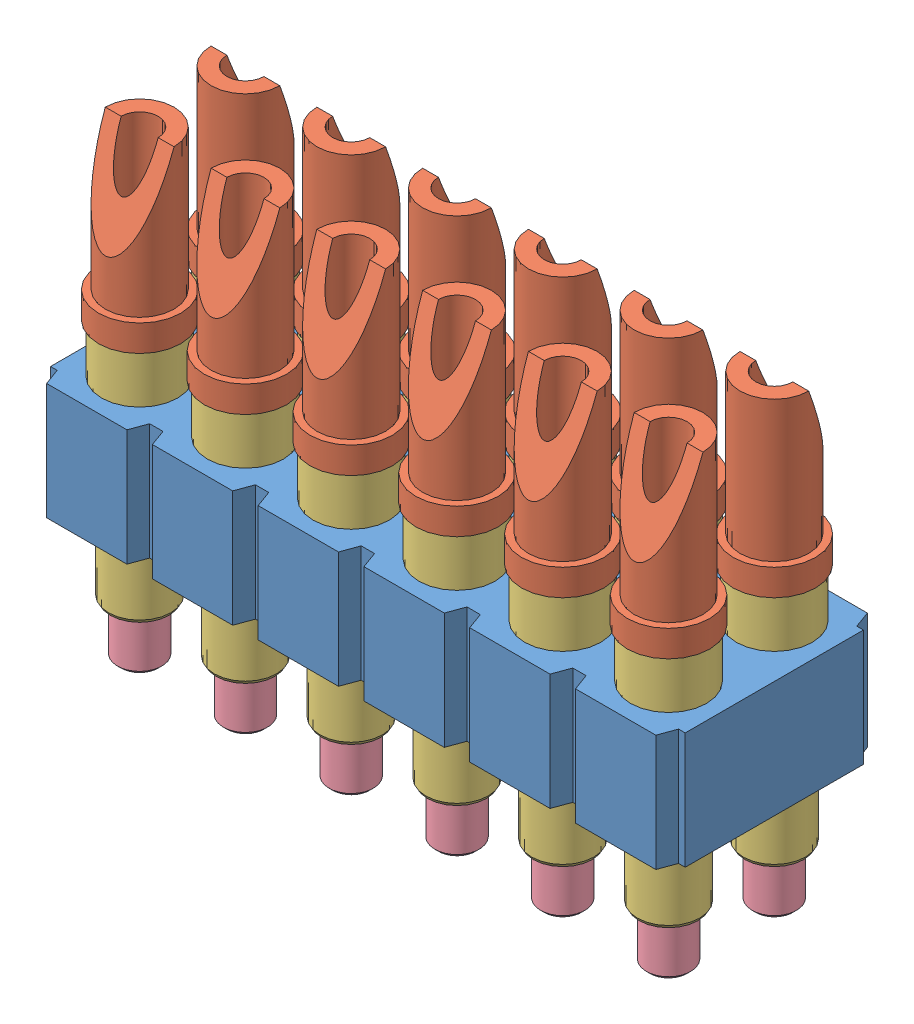
SolidWorks assembly mill-max-826-22-012-00-001000, configuration MillMaxsldprt2014826-XX-XXX-00-0010001220uGoldoverNickelPage12.2off. Lengths in mm.
Overall size (15.24 11.2 5.08).
49 component instances, 5 part files, 14 mates.
Components (placement in the parent):
- mill-max-826-22-012-00-001000_P4XX-28-010-00-090000-1: mill-max-826-22-012-00-001000_P4XX-28-010-00-090000 [P412-28-010-00-090000] at origin size (15.24 2.79 5.08)
- mill-max-826-22-012-00-001000_9370-1: mill-max-826-22-012-00-001000_9370 [9370-0-01-14-00-00-13-0] at (0.9644 -1.8796 -1.27) x (0 1 0) z (1 0 0) size (7.06 1.98 1.98)
- mill-max-826-22-012-00-001000_6950-0-1: mill-max-826-22-012-00-001000_6950-0 [6950-0-02-20-00-00-13-0] at (0.9644 1.1684 -1.27) x (0 -1 0) z (0 0 1) size (5.79 1.83 1.83)
- mill-max-826-22-012-00-001000_0918-5-1: mill-max-826-22-012-00-001000_0918-5 [0918-5-00-20-00-00-13-0] at (0.9644 -1.524 -1.27) x (0 -1 0) z (0 0 1) size (4.5 1.25 1.25)
- mill-max-826-22-012-00-001000_6875-0-00-00-75-XX-43-0C-2: mill-max-826-22-012-00-001000_6875-0-00-00-75-XX-43-0C [6875-0-00-00-75-14-43-0] at (0.9644 -0.2002 -1.27) x (-0.916348 0 0.400384) z (0 -1 0) size (0.98 0.98 3.61)
- mill-max-826-22-012-00-001000_9370-13: mill-max-826-22-012-00-001000_9370 [9370-0-01-14-00-00-13-0] at (0.9644 -1.8796 -3.81) x (0 1 0) z (-1 0 0) size (7.06 1.98 1.98)
- mill-max-826-22-012-00-001000_6950-0-13: mill-max-826-22-012-00-001000_6950-0 [6950-0-02-20-00-00-13-0] at (0.9644 1.1684 -3.81) x (0 -1 0) z (0 0 1) size (5.79 1.83 1.83)
- mill-max-826-22-012-00-001000_0918-5-13: mill-max-826-22-012-00-001000_0918-5 [0918-5-00-20-00-00-13-0] at (0.9644 -1.524 -3.81) x (0 -1 0) z (0 0 1) size (4.5 1.25 1.25)
- mill-max-826-22-012-00-001000_6875-0-00-00-75-XX-43-0C-14: mill-max-826-22-012-00-001000_6875-0-00-00-75-XX-43-0C [6875-0-00-00-75-14-43-0] at (0.9644 -0.2013 -3.81) x (0.913877 0 -0.40599) z (0 -1 0) size (0.98 0.98 3.61)
- mill-max-826-22-012-00-001000_6875-0-00-00-75-XX-43-0C-15: mill-max-826-22-012-00-001000_6875-0-00-00-75-XX-43-0C [6875-0-00-00-75-14-43-0] at (3.5044 -0.2013 -3.81) x (0.913877 0 -0.40599) z (0 -1 0) size (0.98 0.98 3.61)
- mill-max-826-22-012-00-001000_0918-5-14: mill-max-826-22-012-00-001000_0918-5 [0918-5-00-20-00-00-13-0] at (3.5044 -1.524 -3.81) x (0 -1 0) z (0 0 1) size (4.5 1.25 1.25)
- mill-max-826-22-012-00-001000_6950-0-14: mill-max-826-22-012-00-001000_6950-0 [6950-0-02-20-00-00-13-0] at (3.5044 1.1684 -3.81) x (0 -1 0) z (0 0 1) size (5.79 1.83 1.83)
- mill-max-826-22-012-00-001000_9370-14: mill-max-826-22-012-00-001000_9370 [9370-0-01-14-00-00-13-0] at (3.5044 -1.8796 -3.81) x (0 1 0) z (-1 0 0) size (7.06 1.98 1.98)
- mill-max-826-22-012-00-001000_9370-4: mill-max-826-22-012-00-001000_9370 [9370-0-01-14-00-00-13-0] at (3.5044 -1.8796 -1.27) x (0 1 0) z (1 0 0) size (7.06 1.98 1.98)
- mill-max-826-22-012-00-001000_6950-0-4: mill-max-826-22-012-00-001000_6950-0 [6950-0-02-20-00-00-13-0] at (3.5044 1.1684 -1.27) x (0 -1 0) z (0 0 1) size (5.79 1.83 1.83)
- mill-max-826-22-012-00-001000_0918-5-4: mill-max-826-22-012-00-001000_0918-5 [0918-5-00-20-00-00-13-0] at (3.5044 -1.524 -1.27) x (0 -1 0) z (0 0 1) size (4.5 1.25 1.25)
- mill-max-826-22-012-00-001000_6875-0-00-00-75-XX-43-0C-5: mill-max-826-22-012-00-001000_6875-0-00-00-75-XX-43-0C [6875-0-00-00-75-14-43-0] at (3.5044 -0.2002 -1.27) x (-0.916348 0 0.400384) z (0 -1 0) size (0.98 0.98 3.61)
- mill-max-826-22-012-00-001000_6875-0-00-00-75-XX-43-0C-16: mill-max-826-22-012-00-001000_6875-0-00-00-75-XX-43-0C [6875-0-00-00-75-14-43-0] at (6.0444 -0.2013 -3.81) x (0.913877 0 -0.40599) z (0 -1 0) size (0.98 0.98 3.61)
- mill-max-826-22-012-00-001000_6875-0-00-00-75-XX-43-0C-17: mill-max-826-22-012-00-001000_6875-0-00-00-75-XX-43-0C [6875-0-00-00-75-14-43-0] at (8.5844 -0.2013 -3.81) x (0.913877 0 -0.40599) z (0 -1 0) size (0.98 0.98 3.61)
- mill-max-826-22-012-00-001000_6875-0-00-00-75-XX-43-0C-18: mill-max-826-22-012-00-001000_6875-0-00-00-75-XX-43-0C [6875-0-00-00-75-14-43-0] at (11.1244 -0.2013 -3.81) x (0.913877 0 -0.40599) z (0 -1 0) size (0.98 0.98 3.61)
- mill-max-826-22-012-00-001000_6875-0-00-00-75-XX-43-0C-19: mill-max-826-22-012-00-001000_6875-0-00-00-75-XX-43-0C [6875-0-00-00-75-14-43-0] at (13.6644 -0.2013 -3.81) x (0.913877 0 -0.40599) z (0 -1 0) size (0.98 0.98 3.61)
- mill-max-826-22-012-00-001000_0918-5-15: mill-max-826-22-012-00-001000_0918-5 [0918-5-00-20-00-00-13-0] at (6.0444 -1.524 -3.81) x (0 -1 0) z (0 0 1) size (4.5 1.25 1.25)
- mill-max-826-22-012-00-001000_0918-5-16: mill-max-826-22-012-00-001000_0918-5 [0918-5-00-20-00-00-13-0] at (8.5844 -1.524 -3.81) x (0 -1 0) z (0 0 1) size (4.5 1.25 1.25)
- mill-max-826-22-012-00-001000_0918-5-17: mill-max-826-22-012-00-001000_0918-5 [0918-5-00-20-00-00-13-0] at (11.1244 -1.524 -3.81) x (0 -1 0) z (0 0 1) size (4.5 1.25 1.25)
- mill-max-826-22-012-00-001000_0918-5-18: mill-max-826-22-012-00-001000_0918-5 [0918-5-00-20-00-00-13-0] at (13.6644 -1.524 -3.81) x (0 -1 0) z (0 0 1) size (4.5 1.25 1.25)
- mill-max-826-22-012-00-001000_6950-0-15: mill-max-826-22-012-00-001000_6950-0 [6950-0-02-20-00-00-13-0] at (6.0444 1.1684 -3.81) x (0 -1 0) z (0 0 1) size (5.79 1.83 1.83)
- mill-max-826-22-012-00-001000_6950-0-16: mill-max-826-22-012-00-001000_6950-0 [6950-0-02-20-00-00-13-0] at (8.5844 1.1684 -3.81) x (0 -1 0) z (0 0 1) size (5.79 1.83 1.83)
- mill-max-826-22-012-00-001000_6950-0-17: mill-max-826-22-012-00-001000_6950-0 [6950-0-02-20-00-00-13-0] at (11.1244 1.1684 -3.81) x (0 -1 0) z (0 0 1) size (5.79 1.83 1.83)
- mill-max-826-22-012-00-001000_6950-0-18: mill-max-826-22-012-00-001000_6950-0 [6950-0-02-20-00-00-13-0] at (13.6644 1.1684 -3.81) x (0 -1 0) z (0 0 1) size (5.79 1.83 1.83)
- mill-max-826-22-012-00-001000_9370-15: mill-max-826-22-012-00-001000_9370 [9370-0-01-14-00-00-13-0] at (6.0444 -1.8796 -3.81) x (0 1 0) z (-1 0 0) size (7.06 1.98 1.98)
- mill-max-826-22-012-00-001000_9370-16: mill-max-826-22-012-00-001000_9370 [9370-0-01-14-00-00-13-0] at (8.5844 -1.8796 -3.81) x (0 1 0) z (-1 0 0) size (7.06 1.98 1.98)
- mill-max-826-22-012-00-001000_9370-17: mill-max-826-22-012-00-001000_9370 [9370-0-01-14-00-00-13-0] at (11.1244 -1.8796 -3.81) x (0 1 0) z (-1 0 0) size (7.06 1.98 1.98)
- mill-max-826-22-012-00-001000_9370-18: mill-max-826-22-012-00-001000_9370 [9370-0-01-14-00-00-13-0] at (13.6644 -1.8796 -3.81) x (0 1 0) z (-1 0 0) size (7.06 1.98 1.98)
- mill-max-826-22-012-00-001000_9370-9: mill-max-826-22-012-00-001000_9370 [9370-0-01-14-00-00-13-0] at (6.0444 -1.8796 -1.27) x (0 1 0) z (1 0 0) size (7.06 1.98 1.98)
- mill-max-826-22-012-00-001000_9370-10: mill-max-826-22-012-00-001000_9370 [9370-0-01-14-00-00-13-0] at (8.5844 -1.8796 -1.27) x (0 1 0) z (1 0 0) size (7.06 1.98 1.98)
- mill-max-826-22-012-00-001000_9370-11: mill-max-826-22-012-00-001000_9370 [9370-0-01-14-00-00-13-0] at (11.1244 -1.8796 -1.27) x (0 1 0) z (1 0 0) size (7.06 1.98 1.98)
- mill-max-826-22-012-00-001000_9370-12: mill-max-826-22-012-00-001000_9370 [9370-0-01-14-00-00-13-0] at (13.6644 -1.8796 -1.27) x (0 1 0) z (1 0 0) size (7.06 1.98 1.98)
- mill-max-826-22-012-00-001000_6950-0-9: mill-max-826-22-012-00-001000_6950-0 [6950-0-02-20-00-00-13-0] at (6.0444 1.1684 -1.27) x (0 -1 0) z (0 0 1) size (5.79 1.83 1.83)
- mill-max-826-22-012-00-001000_6950-0-10: mill-max-826-22-012-00-001000_6950-0 [6950-0-02-20-00-00-13-0] at (8.5844 1.1684 -1.27) x (0 -1 0) z (0 0 1) size (5.79 1.83 1.83)
- mill-max-826-22-012-00-001000_6950-0-11: mill-max-826-22-012-00-001000_6950-0 [6950-0-02-20-00-00-13-0] at (11.1244 1.1684 -1.27) x (0 -1 0) z (0 0 1) size (5.79 1.83 1.83)
- mill-max-826-22-012-00-001000_6950-0-12: mill-max-826-22-012-00-001000_6950-0 [6950-0-02-20-00-00-13-0] at (13.6644 1.1684 -1.27) x (0 -1 0) z (0 0 1) size (5.79 1.83 1.83)
- mill-max-826-22-012-00-001000_0918-5-9: mill-max-826-22-012-00-001000_0918-5 [0918-5-00-20-00-00-13-0] at (6.0444 -1.524 -1.27) x (0 -1 0) z (0 0 1) size (4.5 1.25 1.25)
- mill-max-826-22-012-00-001000_0918-5-10: mill-max-826-22-012-00-001000_0918-5 [0918-5-00-20-00-00-13-0] at (8.5844 -1.524 -1.27) x (0 -1 0) z (0 0 1) size (4.5 1.25 1.25)
- mill-max-826-22-012-00-001000_0918-5-11: mill-max-826-22-012-00-001000_0918-5 [0918-5-00-20-00-00-13-0] at (11.1244 -1.524 -1.27) x (0 -1 0) z (0 0 1) size (4.5 1.25 1.25)
- mill-max-826-22-012-00-001000_0918-5-12: mill-max-826-22-012-00-001000_0918-5 [0918-5-00-20-00-00-13-0] at (13.6644 -1.524 -1.27) x (0 -1 0) z (0 0 1) size (4.5 1.25 1.25)
- mill-max-826-22-012-00-001000_6875-0-00-00-75-XX-43-0C-10: mill-max-826-22-012-00-001000_6875-0-00-00-75-XX-43-0C [6875-0-00-00-75-14-43-0] at (6.0444 -0.2002 -1.27) x (-0.916348 0 0.400384) z (0 -1 0) size (0.98 0.98 3.61)
- mill-max-826-22-012-00-001000_6875-0-00-00-75-XX-43-0C-11: mill-max-826-22-012-00-001000_6875-0-00-00-75-XX-43-0C [6875-0-00-00-75-14-43-0] at (8.5844 -0.2002 -1.27) x (-0.916348 0 0.400384) z (0 -1 0) size (0.98 0.98 3.61)
- mill-max-826-22-012-00-001000_6875-0-00-00-75-XX-43-0C-12: mill-max-826-22-012-00-001000_6875-0-00-00-75-XX-43-0C [6875-0-00-00-75-14-43-0] at (11.1244 -0.2002 -1.27) x (-0.916348 0 0.400384) z (0 -1 0) size (0.98 0.98 3.61)
- mill-max-826-22-012-00-001000_6875-0-00-00-75-XX-43-0C-13: mill-max-826-22-012-00-001000_6875-0-00-00-75-XX-43-0C [6875-0-00-00-75-14-43-0] at (13.6644 -0.2002 -1.27) x (-0.916348 0 0.400384) z (0 -1 0) size (0.98 0.98 3.61)
Mates (geometry in assembly coordinates):
- Coincident1: coincident anti-aligned: plane of mill-max-826-22-012-00-001000_9370-1 through (0.9644 1.1684 -0.6159) normal (0 -1 0); plane of mill-max-826-22-012-00-001000_6950-0-1 through (0.9644 1.1684 -1.27) normal (0 1 0)
- Concentric1: concentric anti-aligned: cylinder of mill-max-826-22-012-00-001000_9370-1 through (0.9644 -1.8796 -1.27) axis (0 -1 0) radius 0.6541; cylinder of mill-max-826-22-012-00-001000_6950-0-1 through (0.9644 1.1684 -1.27) axis (0 1 0) radius 0.6477
- Distance1: distance = 3.0988 mm anti-aligned: plane of mill-max-826-22-012-00-001000_0918-5-1; plane of mill-max-826-22-012-00-001000_6950-0-1 through (1.6697 -4.6228 -1.27) normal (0 -1 0)
- Concentric2: concentric aligned: cylinder of mill-max-826-22-012-00-001000_6950-0-1 through (0.9644 1.1684 -1.27) axis (0 1 0) radius 0.5524; cylinder of mill-max-826-22-012-00-001000_0918-5-1 through (0.9644 -1.524 -1.27) axis (0 1 0) radius 0.6236
- Concentric3: concentric aligned: cylinder of mill-max-826-22-012-00-001000_9370-1 through (0.9644 -1.8796 -1.27) axis (0 -1 0) radius 0.2159; line of mill-max-826-22-012-00-001000_6875-0-00-00-75-XX-43-0C-2 through (0.9644 0.0961 -1.27) axis (0 -1 0)
- Coincident3: coincident anti-aligned: plane of mill-max-826-22-012-00-001000_P4XX-28-010-00-090000-1 through (-0.1456 0 -4.68) normal (0 1 0); plane of mill-max-826-22-012-00-001000_6950-0-1 through (1.8788 0 -1.27) normal (0 -1 0)
- Concentric6: concentric aligned: cylinder of mill-max-826-22-012-00-001000_P4XX-28-010-00-090000-1 through (0.9644 0 -1.27) axis (0 1 0) radius 0.8014; cylinder of mill-max-826-22-012-00-001000_6950-0-1 through (0.9644 1.1684 -1.27) axis (0 1 0) radius 0.7493
- Coincident4: coincident anti-aligned: plane of mill-max-826-22-012-00-001000_9370-13 through (0.9644 1.1684 -4.464) normal (0 -1 0); plane of mill-max-826-22-012-00-001000_6950-0-13 through (0.9644 1.1684 -3.81) normal (0 1 0)
- Concentric7: concentric anti-aligned: cylinder of mill-max-826-22-012-00-001000_9370-13 through (0.9644 -1.8796 -3.81) axis (0 -1 0) radius 0.6541; cylinder of mill-max-826-22-012-00-001000_6950-0-13 through (0.9644 1.1684 -3.81) axis (0 1 0) radius 0.6477
- Distance2: distance = 3.0988 mm anti-aligned: plane of mill-max-826-22-012-00-001000_0918-5-13; plane of mill-max-826-22-012-00-001000_6950-0-13 through (1.6697 -4.6228 -3.81) normal (0 -1 0)
- Concentric8: concentric aligned: cylinder of mill-max-826-22-012-00-001000_6950-0-13 through (0.9644 1.1684 -3.81) axis (0 1 0) radius 0.5524; cylinder of mill-max-826-22-012-00-001000_0918-5-13 through (0.9644 -1.524 -3.81) axis (0 1 0) radius 0.6236
- Concentric9: concentric aligned: cylinder of mill-max-826-22-012-00-001000_9370-13 through (0.9644 -1.8796 -3.81) axis (0 -1 0) radius 0.2159; line of mill-max-826-22-012-00-001000_6875-0-00-00-75-XX-43-0C-14 through (0.9644 0.095 -3.81) axis (0 -1 0)
- Coincident6: coincident anti-aligned: plane of mill-max-826-22-012-00-001000_P4XX-28-010-00-090000-1 through (-0.1456 0 -4.68) normal (0 1 0); plane of mill-max-826-22-012-00-001000_6950-0-13 through (1.8788 0 -3.81) normal (0 -1 0)
- Concentric10: concentric aligned: cylinder of mill-max-826-22-012-00-001000_P4XX-28-010-00-090000-1 through (0.9644 0 -3.81) axis (0 1 0) radius 0.8014; cylinder of mill-max-826-22-012-00-001000_6950-0-13 through (0.9644 1.1684 -3.81) axis (0 1 0) radius 0.7493
